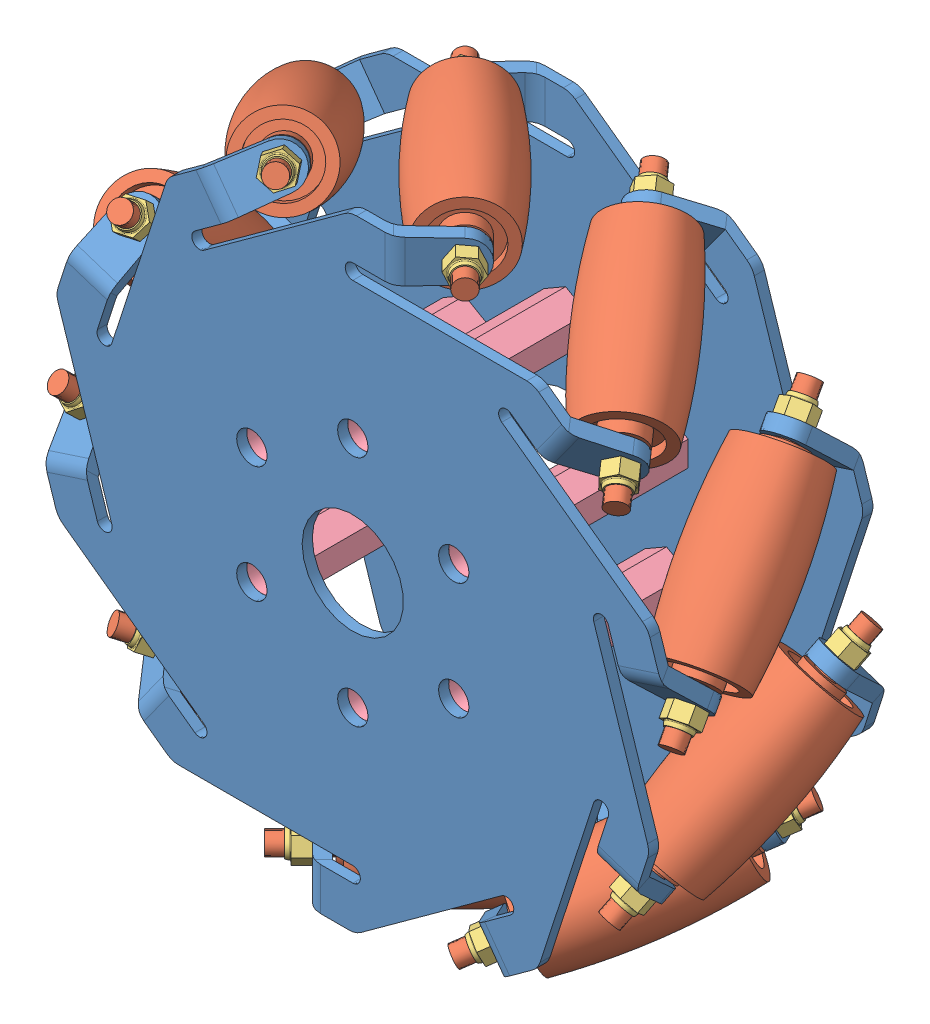
SolidWorks assembly 麦克纳姆轮装配（2）, configuration 默认. Lengths in mm.
Overall size (73.19 68.37 28.98).
38 component instances, 4 part files, 28 mates.
Components (placement in the parent):
- 麦克纳姆轮（2）-1: 麦克纳姆轮（2） [默认] at (4.7846 1.1432 62.959) size (62.96 61.4 5.95)
- 麦克纳姆轮（2）-2: 麦克纳姆轮（2） [默认] at (4.7846 1.1432 85.0986) x (-1 0 0) z (0 0 -1) size (62.96 61.4 5.95)
- 辊子-1: 辊子 [默认] at (-6.5323 29.7426 62.712) x (0.707107 0 0.707107) z (-0.707107 0 0.707107) size (28 9.23 9.23)
- 辊子-2: 辊子 [默认] at (-21.1917 17.6211 62.6991) x (0.572061 0.415627 0.707107) z (-0.707107 -0.186947 0.681946) size (28 9.23 9.23)
- 辊子-3: 辊子 [默认] at (-25.9161 -0.7943 62.6991) x (0.218508 0.672499 0.707107) z (-0.650722 -0.439573 0.619142) size (28 9.23 9.23)
- 辊子-4: 辊子 [默认] at (-25.9121 3.0685 85.3457) x (0.218508 -0.672499 -0.707107) z (0.395342 -0.60148 0.694209) size (28 9.23 9.23)
- 辊子-6: 辊子 [默认] at (-21.1812 -15.3423 85.3457) x (0.572061 -0.415627 -0.707107) z (0.647393 -0.300533 0.700401) size (28 9.23 9.23)
- 辊子-7: 辊子 [默认] at (-6.5323 -27.4561 85.3457) x (0.707107 0 -0.707107) z (0.705301 0.071414 0.705301) size (28 9.23 9.23)
- 辊子-8: 辊子 [默认] at (12.4393 -28.646 85.3457) x (0.572061 0.415627 -0.707107) z (0.714443 0.170963 0.678486) size (28 9.23 9.23)
- 辊子-9: 辊子 [默认] at (35.4853 3.0808 62.6991) x (-0.218508 -0.672499 0.707107) z (-0.954109 -0.00482 -0.29942) size (28 9.23 9.23)
- 辊子-10: 辊子 [默认] at (28.4831 20.7562 62.6991) x (0.218508 -0.672499 0.707107) z (-0.771684 0.324444 0.547028) size (28 9.23 9.23)
- 辊子-11: 辊子 [默认] at (12.4289 30.9401 62.6991) x (0.572061 -0.415627 0.707107) z (-0.689 0.22422 0.689206) size (28 9.23 9.23)
- M2【螺母】-1: M2【螺母】 [默认] at (-5.0722 29.3326 82.6238) x (0.808299 -0.139279 -0.572061) z (-0.572061 -0.415627 -0.707107) size (2.79 3.22 1.95)
- M2【螺母】-2: M2【螺母】 [默认] at (13.3795 29.7426 82.6238) x (0.572061 -0.587785 -0.572061) z (-0.707107 0 -0.707107) size (2.79 3.22 1.95)
- M2【螺母】-3: M2【螺母】 [默认] at (28.5483 19.2286 82.6238) x (0.117316 -0.811778 -0.572061) z (-0.572061 0.415627 -0.707107) size (2.79 3.22 1.95)
- M2【螺母】-4: M2【螺母】 [默认] at (34.6402 1.8066 82.6238) x (-0.38224 -0.725698 -0.572061) z (-0.218508 0.672499 -0.707107) size (2.79 3.22 1.95)
- M2【螺母】-5: M2【螺母】 [默认] at (29.3282 -15.8687 82.6238) x (-0.735794 -0.362427 -0.572061) z (0.218508 0.672499 -0.707107) size (2.79 3.22 1.95)
- M2【螺母】-6: M2【螺母】 [默认] at (14.6414 -27.0461 82.6238) x (-0.808299 0.139279 -0.572061) z (0.572061 0.415627 -0.707107) size (2.79 3.22 1.95)
- M2【螺母】-7: M2【螺母】 [默认] at (-3.8104 -27.4561 82.6238) x (-0.572061 0.587785 -0.572061) z (0.707107 0 -0.707107) size (2.79 3.22 1.95)
- M2【螺母】-8: M2【螺母】 [默认] at (-18.9791 -16.9422 82.6238) x (-0.117316 0.811778 -0.572061) z (0.572061 -0.415627 -0.707107) size (2.79 3.22 1.95)
- M2【螺母】-9: M2【螺母】 [默认] at (-25.071 0.4798 82.6238) x (0.38224 0.725698 -0.572061) z (0.218508 -0.672499 -0.707107) size (2.79 3.22 1.95)
- M2【螺母】-10: M2【螺母】 [默认] at (-19.759 18.1552 82.6238) x (0.735794 0.362427 -0.572061) z (-0.218508 -0.672499 -0.707107) size (2.79 3.22 1.95)
- M2【螺母】-11: M2【螺母】 [默认] at (-19.759 -15.8687 65.4339) x (0.972031 0.086079 0.218508) z (-0.218508 0.672499 0.707107) size (2.79 3.22 1.95)
- M2【螺母】-12: M2【螺母】 [默认] at (-5.0722 -27.0461 65.4339) x (0.735794 0.640985 0.218508) z (-0.572061 0.415627 0.707107) size (2.79 3.22 1.95)
- M2【螺母】-13: M2【螺母】 [默认] at (13.3795 -27.4561 65.4339) x (0.218508 0.951057 0.218508) z (-0.707107 0 0.707107) size (2.79 3.22 1.95)
- M2【螺母】-14: M2【螺母】 [默认] at (28.5483 -16.9422 65.4339) x (-0.38224 0.897857 0.218508) z (-0.572061 -0.415627 0.707107) size (2.79 3.22 1.95)
- M2【螺母】-15: M2【螺母】 [默认] at (34.6402 0.4798 65.4339) x (-0.836986 0.501706 0.218508) z (-0.218508 -0.672499 0.707107) size (2.79 3.22 1.95)
- M2【螺母】-16: M2【螺母】 [默认] at (29.3282 18.1552 65.4339) x (-0.972031 -0.086079 0.218508) z (0.218508 -0.672499 0.707107) size (2.79 3.22 1.95)
- M2【螺母】-17: M2【螺母】 [默认] at (14.6414 29.3326 65.4339) x (-0.735794 -0.640985 0.218508) z (0.572061 -0.415627 0.707107) size (2.79 3.22 1.95)
- M2【螺母】-18: M2【螺母】 [默认] at (-3.8104 29.7426 65.4339) x (-0.218508 -0.951057 0.218508) z (0.707107 0 0.707107) size (2.79 3.22 1.95)
- M2【螺母】-19: M2【螺母】 [默认] at (-18.9791 19.2286 65.4339) x (0.38224 -0.897857 0.218508) z (0.572061 0.415627 0.707107) size (2.79 3.22 1.95)
- M2【螺母】-20: M2【螺母】 [默认] at (-25.071 1.8066 65.4339) x (0.836986 -0.501706 0.218508) z (0.218508 0.672499 0.707107) size (2.79 3.22 1.95)
- 20mm长-M3【六角铜柱】-1: 20mm长-M3【六角铜柱】 [默认] at (14.7439 -4.6068 64.0986) size (4.27 4.93 20)
- 20mm长-M3【六角铜柱】-2: 20mm长-M3【六角铜柱】 [默认] at (4.7846 -10.3568 64.0986) x (0.5 -0.866025 0) z (0 0 1) size (4.27 4.93 20)
- 20mm长-M3【六角铜柱】-3: 20mm长-M3【六角铜柱】 [默认] at (-5.1747 -4.6068 64.0986) x (-0.5 -0.866025 0) z (0 0 1) size (4.27 4.93 20)
- 20mm长-M3【六角铜柱】-4: 20mm长-M3【六角铜柱】 [默认] at (-5.1747 6.8932 64.0986) x (-1 0 0) z (0 0 1) size (4.27 4.93 20)
- 20mm长-M3【六角铜柱】-5: 20mm长-M3【六角铜柱】 [默认] at (4.7846 12.6432 64.0986) x (-0.5 0.866025 0) z (0 0 1) size (4.27 4.93 20)
- 20mm长-M3【六角铜柱】-6: 20mm长-M3【六角铜柱】 [默认] at (14.7439 6.8932 64.0986) x (0.5 0.866025 0) z (0 0 1) size (4.27 4.93 20)
Mates (geometry in assembly coordinates):
- 同心1: concentric: cylinder of assembly; cylinder of assembly; cylinder of 麦克纳姆轮（2）-1 through (4.7846 1.1432 62.959) axis (0 0 1) radius 5; cylinder of 麦克纳姆轮（2）-2 through (4.7846 1.1432 85.0986) axis (0 0 -1) radius 5
- 同心2: concentric: cylinder of assembly; cylinder of assembly; cylinder of 麦克纳姆轮（2）-1 through (-6.6994 29.7426 62.5448) axis (0.707107 0 0.707107) radius 1; cylinder of 辊子-1 through (-5.1084 29.7426 64.1358) axis (0.707107 0 0.707107) radius 1
- 同心3: concentric: cylinder of assembly; cylinder of assembly; cylinder of 麦克纳姆轮（2）-2 through (16.2686 29.7426 85.5129) axis (-0.707107 0 -0.707107) radius 1; cylinder of 辊子-1 through (14.6905 29.7426 83.9348) axis (-0.707107 0 -0.707107) radius 1
- 距离1: distance = 0.25 mm: plane of assembly; plane of assembly; plane of 辊子-1 through (-1.5729 29.7426 67.6713) normal (-0.707107 0 -0.707107); plane of 麦克纳姆轮（2）-1 through (-3.1639 27.6432 68.9088) normal (0.707107 0 0.707107)
- 同心4: concentric: cylinder of assembly; cylinder of assembly; cylinder of 麦克纳姆轮（2）-2 through (-2.7349 31.0307 85.5129) axis (-0.572061 -0.415627 -0.707107) radius 1; cylinder of 辊子-2 through (-4.0221 30.0956 83.9219) axis (-0.572061 -0.415627 -0.707107) radius 1
- 距离2: distance = 0.25 mm: plane of assembly; plane of assembly; plane of 辊子-2 through (-6.8824 28.0174 80.3863) normal (0.572061 0.415627 0.707107); plane of 麦克纳姆轮（2）-2 through (-4.3612 27.2542 79.1489) normal (-0.572061 -0.415627 -0.707107)
- 同心5: concentric: cylinder of assembly; cylinder of assembly; cylinder of 麦克纳姆轮（2）-2 through (-18.8663 20.9029 85.5129) axis (-0.218508 -0.672499 -0.707107) radius 1; cylinder of 辊子-3 through (-19.3579 19.3898 83.9219) axis (-0.218508 -0.672499 -0.707107) radius 1
- 同心7: concentric: cylinder of assembly; cylinder of assembly; cylinder of 麦克纳姆轮（2）-2 through (-25.9638 3.2275 85.5129) axis (0.218508 -0.672499 -0.707107) radius 1; cylinder of 辊子-4 through (-25.4721 1.7144 83.9219) axis (0.218508 -0.672499 -0.707107) radius 1
- 同心8: concentric: cylinder of assembly; cylinder of assembly; cylinder of 麦克纳姆轮（2）-2 through (-21.3165 -15.244 85.5129) axis (0.572061 -0.415627 -0.707107) radius 1; cylinder of 辊子-6 through (-20.0293 -16.1792 83.9219) axis (0.572061 -0.415627 -0.707107) radius 1
- 同心9: concentric: cylinder of assembly; cylinder of assembly; cylinder of 麦克纳姆轮（2）-2 through (-6.6994 -27.4561 85.5129) axis (0.707107 0 -0.707107) radius 1; cylinder of 辊子-7 through (-5.1084 -27.4561 83.9219) axis (0.707107 0 -0.707107) radius 1
- 同心10: concentric: cylinder of assembly; cylinder of assembly; cylinder of 麦克纳姆轮（2）-2 through (12.3041 -28.7443 85.5129) axis (0.572061 0.415627 -0.707107) radius 1; cylinder of 辊子-8 through (13.5912 -27.8091 83.9219) axis (0.572061 0.415627 -0.707107) radius 1
- 同心11: concentric: cylinder of assembly; cylinder of assembly; cylinder of 麦克纳姆轮（2）-2 through (28.4354 -18.6164 85.5129) axis (0.218508 0.672499 -0.707107) radius 1; cylinder of 辊子-9 through (28.9271 -17.1033 83.9219) axis (0.218508 0.672499 -0.707107) radius 1
- 同心12: concentric: cylinder of assembly; cylinder of assembly; cylinder of 麦克纳姆轮（2）-2 through (35.533 -0.941 85.5129) axis (-0.218508 0.672499 -0.707107) radius 1; cylinder of 辊子-10 through (35.0413 0.5721 83.9219) axis (-0.218508 0.672499 -0.707107) radius 1
- 同心13: concentric: cylinder of assembly; cylinder of assembly; cylinder of 麦克纳姆轮（2）-2 through (30.8857 17.5305 85.5129) axis (-0.572061 0.415627 -0.707107) radius 1; cylinder of 辊子-11 through (29.5985 18.4656 83.9219) axis (-0.572061 0.415627 -0.707107) radius 1
- 距离3: distance = 0.25 mm: plane of 辊子-3 through (-20.4504 16.0273 80.3863) normal (0.218508 0.672499 0.707107); plane of 麦克纳姆轮（2）-2 through (-17.9622 16.8916 79.1489) normal (-0.218508 -0.672499 -0.707107)
- 距离4: distance = 0.25 mm: plane of 辊子-4 through (-24.3796 -1.6481 80.3863) normal (-0.218508 0.672499 0.707107); plane of 麦克纳姆轮（2）-2 through (-22.8746 0.5137 79.1489) normal (0.218508 -0.672499 -0.707107)
- 距离5: distance = 0.25 mm: plane of 辊子-6 through (-17.169 -18.2573 80.3863) normal (-0.572061 0.415627 0.707107); plane of 麦克纳姆轮（2）-2 through (-17.2222 -15.6237 79.1489) normal (0.572061 -0.415627 -0.707107)
- 距离6: distance = 0.25 mm: plane of 辊子-7 through (-1.5729 -27.4561 80.3863) normal (-0.707107 0 0.707107); plane of 麦克纳姆轮（2）-2 through (-3.1639 -25.3568 79.1489) normal (0.707107 0 -0.707107)
- 距离7: distance = 0.25 mm: plane of 辊子-8 through (16.4515 -25.731 80.3863) normal (-0.572061 -0.415627 0.707107); plane of 麦克纳姆轮（2）-2 through (13.9304 -24.9677 79.1489) normal (0.572061 0.415627 -0.707107)
- 距离8: distance = 0.25 mm: plane of 辊子-9 through (30.0196 -13.7408 80.3863) normal (-0.218508 -0.672499 0.707107); plane of 麦克纳姆轮（2）-2 through (27.5314 -14.6052 79.1489) normal (0.218508 0.672499 -0.707107)
- 距离9: distance = 0.25 mm: plane of 辊子-10 through (33.9488 3.9346 80.3863) normal (0.218508 -0.672499 0.707107); plane of 麦克纳姆轮（2）-2 through (32.4438 1.7727 79.1489) normal (-0.218508 0.672499 -0.707107)
- 距离10: distance = 0.25 mm: plane of 辊子-11 through (26.7382 20.5437 80.3863) normal (0.572061 -0.415627 0.707107); plane of 麦克纳姆轮（2）-2 through (26.7914 17.9102 79.1489) normal (-0.572061 0.415627 -0.707107)
- 重合1: coincident: plane of assembly; plane of assembly; plane of 麦克纳姆轮（2）-2 through (-6.0202 31.2388 80.1489) normal (0.572061 0.415627 0.707107); plane of M2【螺母】-1 through (-5.9303 28.7091 81.5631) normal (-0.572061 -0.415627 -0.707107)
- 同心15: concentric: cylinder of 辊子-2 through (-4.0221 30.0956 83.9219) axis (-0.572061 -0.415627 -0.707107) radius 1; cylinder of M2【螺母】-1 through (-5.9303 28.7091 81.5631) axis (0.572061 0.415627 0.707107) radius 1
- 重合2: coincident: plane of 麦克纳姆轮（2）-1 through (-21.6464 -16.8537 67.9088) normal (0.218508 -0.672499 -0.707107); plane of M2【螺母】-11 through (-20.0868 -14.86 66.4945) normal (-0.218508 0.672499 0.707107)
- 同心16: concentric: cylinder of 辊子-4 through (-19.3539 -17.1156 64.1229) axis (-0.218508 0.672499 0.707107) radius 1; cylinder of M2【螺母】-11 through (-20.0868 -14.86 66.4945) axis (0.218508 -0.672499 -0.707107) radius 1
- 同心17: concentric: cylinder of assembly; cylinder of assembly; cylinder of 麦克纳姆轮（2）-2 through (14.7439 -4.6068 85.0986) axis (0 0 -1) radius 1.5; cylinder of 20mm长-M3【六角铜柱】-1 through (14.7439 -4.6068 84.0986) axis (0 0 -1) radius 1.5; plane of assembly; plane of assembly; plane of 麦克纳姆轮（2）-2; plane of 20mm长-M3【六角铜柱】-1
- 重合3: coincident: plane of 麦克纳姆轮（2）-2 through (4.7846 26.8932 84.0986) normal (0 0 -1); plane of 20mm长-M3【六角铜柱】-1 through (14.7439 -4.6068 84.0986) normal (0 0 1)
